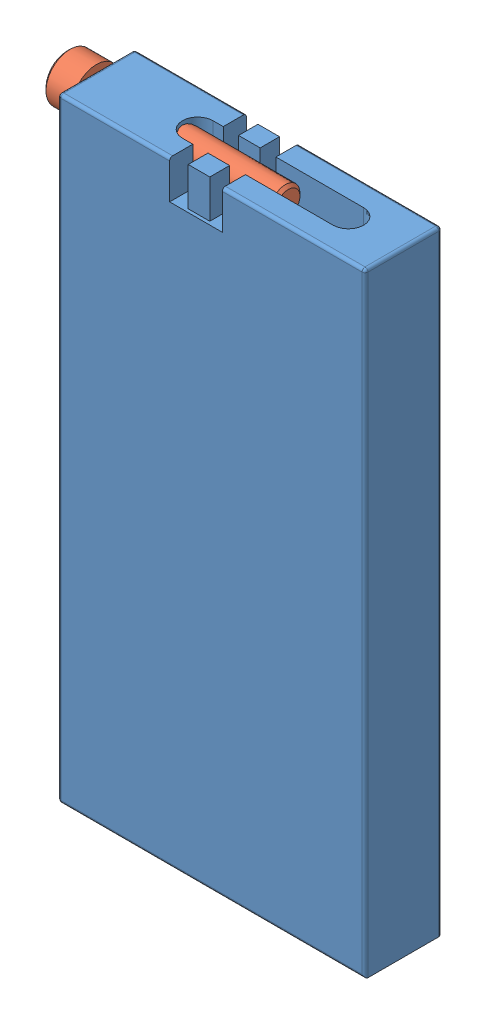
SolidWorks assembly Tetrix Chain Breaker Tool, configuration Default. Lengths in mm.
Overall size (55.63 102.52 12.7).
2 component instances, 2 part files, 0 mates.
Components (placement in the parent):
- Tetrix Chain Breaker Block-1: Tetrix Chain Breaker Block [Default] at origin size (50.8 101.6 12.7)
- Tetrix Chain Breaker Screw-1: Tetrix Chain Breaker Screw [Default] at (-10.8796 3.302 0) x (0 1 0) z (0 0 1) size (7.94 36.58 7.94)
